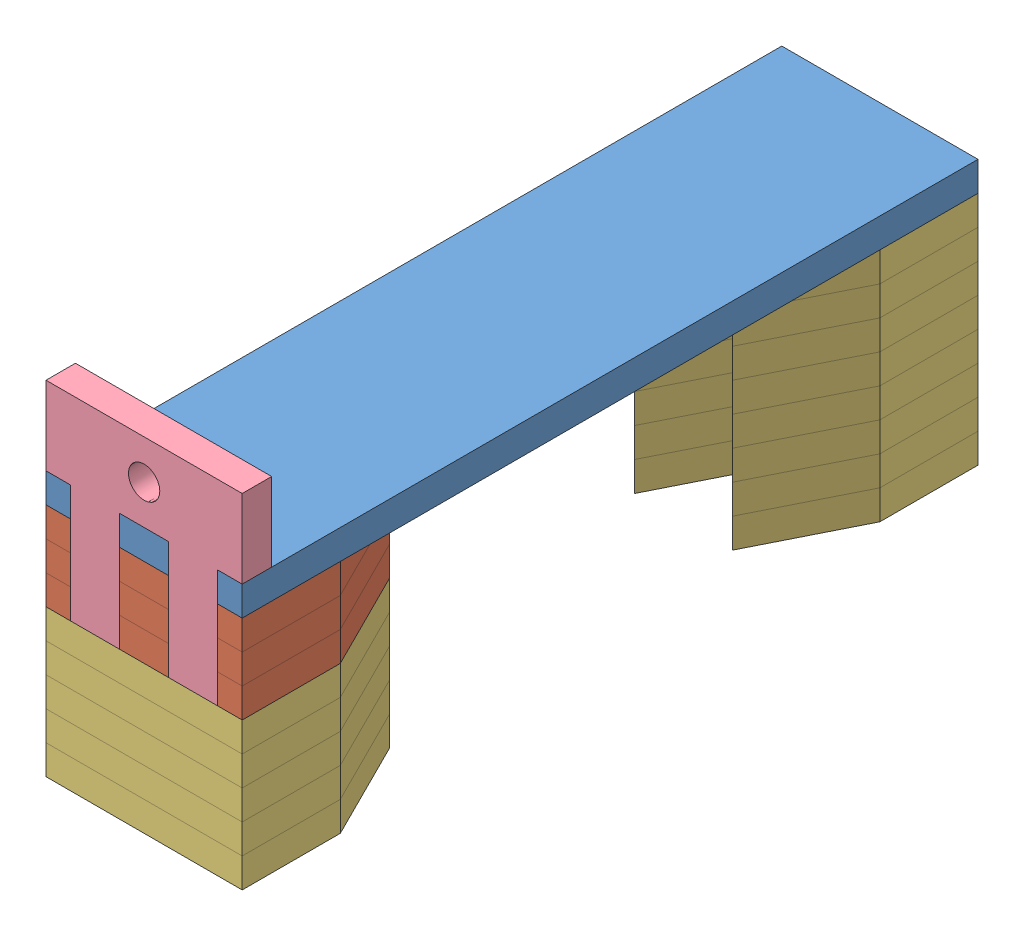
SolidWorks assembly piston, configuration Default. Lengths in mm.
Overall size (20 35 75).
18 component instances, 4 part files, 51 mates.
Components (placement in the parent):
- tooth-strip-1: tooth-strip [Default] at (26.7289 41.9083 55.3369) size (20 3 75)
- tooth-piston-1: tooth-piston [Default] at (26.7289 35.9083 82.8369) x (-1 0 0) z (0 0 -1) size (20 3 20)
- tooth-piston-2: tooth-piston [Default] at (26.7289 38.9083 82.8369) x (-1 0 0) z (0 0 -1) size (20 3 20)
- tooth-end-1: tooth-end [Default] at (26.7289 38.9083 27.8369) size (20 3 20)
- tooth-end-2: tooth-end [Default] at (26.7289 35.9083 27.8369) size (20 3 20)
- tooth-piston-3: tooth-piston [Default] at (26.7289 32.9083 82.8369) x (-1 0 0) z (0 0 -1) size (20 3 20)
- tooth-end-3: tooth-end [Default] at (26.7289 32.9083 27.8369) size (20 3 20)
- stopper-1: stopper [Default] at (16.7289 32.9083 89.8369) x (1 0 0) z (0 -1 0) size (20 3 20)
- tooth-end-4: tooth-end [Default] at (26.7289 29.9083 27.8369) size (20 3 20)
- tooth-end-5: tooth-end [Default] at (26.7289 29.9083 82.8369) x (-1 0 0) z (0 0 -1) size (20 3 20)
- tooth-end-6: tooth-end [Default] at (26.7289 26.9083 27.8369) size (20 3 20)
- tooth-end-7: tooth-end [Default] at (26.7289 23.9083 27.8369) size (20 3 20)
- tooth-end-8: tooth-end [Default] at (26.7289 26.9083 82.8369) x (-1 0 0) z (0 0 -1) size (20 3 20)
- tooth-end-9: tooth-end [Default] at (26.7289 23.9083 82.8369) x (-1 0 0) z (0 0 -1) size (20 3 20)
- tooth-end-10: tooth-end [Default] at (26.7289 20.9083 27.8369) size (20 3 20)
- tooth-end-11: tooth-end [Default] at (26.7289 17.9083 27.8369) size (20 3 20)
- tooth-end-12: tooth-end [Default] at (26.7289 20.9083 82.8369) x (-1 0 0) z (0 0 -1) size (20 3 20)
- tooth-end-13: tooth-end [Default] at (26.7289 17.9083 82.8369) x (-1 0 0) z (0 0 -1) size (20 3 20)
Mates (geometry in assembly coordinates):
- Coincident1: coincident anti-aligned: plane of tooth-strip-1 through (26.7289 41.9083 55.3369) normal (0 -1 0); plane of tooth-piston-2 through (26.7289 41.9083 82.8369) normal (0 1 0)
- Coincident2: coincident aligned: plane of tooth-strip-1 through (36.7289 44.9083 92.8369) normal (1 0 0); plane of tooth-piston-2 through (36.7289 41.9083 72.8369) normal (1 0 0)
- Coincident3: coincident aligned: plane of tooth-strip-1 through (16.7289 44.9083 92.8369) normal (0 0 1); plane of tooth-piston-2 through (36.7289 41.9083 92.8369) normal (0 0 1)
- Coincident4: coincident anti-aligned: plane of tooth-piston-1 through (26.7289 38.9083 82.8369) normal (0 1 0); plane of tooth-piston-2 through (26.7289 38.9083 82.8369) normal (0 -1 0)
- Coincident5: coincident aligned: plane of tooth-piston-1 through (36.7289 38.9083 72.8369) normal (1 0 0); plane of tooth-piston-2 through (36.7289 41.9083 72.8369) normal (1 0 0)
- Coincident6: coincident aligned: plane of tooth-piston-1 through (36.7289 38.9083 92.8369) normal (0 0 1); plane of tooth-piston-2 through (36.7289 41.9083 92.8369) normal (0 0 1)
- Coincident7: coincident anti-aligned: plane of tooth-strip-1 through (26.7289 41.9083 55.3369) normal (0 -1 0); plane of tooth-end-1 through (26.7289 41.9083 27.8369) normal (0 1 0)
- Coincident8: coincident aligned: plane of tooth-strip-1 through (16.7289 44.9083 17.8369) normal (0 0 -1); plane of tooth-end-1 through (16.7289 41.9083 17.8369) normal (0 0 -1)
- Coincident9: coincident aligned: plane of tooth-strip-1 through (36.7289 44.9083 92.8369) normal (1 0 0); plane of tooth-end-1 through (36.7289 41.9083 37.8369) normal (1 0 0)
- Coincident10: coincident anti-aligned: plane of tooth-end-1 through (26.7289 38.9083 27.8369) normal (0 -1 0); plane of tooth-end-2 through (26.7289 38.9083 27.8369) normal (0 1 0)
- Coincident11: coincident aligned: plane of tooth-end-1 through (36.7289 41.9083 37.8369) normal (1 0 0); plane of tooth-end-2 through (36.7289 38.9083 37.8369) normal (1 0 0)
- Coincident12: coincident aligned: plane of tooth-end-1 through (16.7289 41.9083 17.8369) normal (0 0 -1); plane of tooth-end-2 through (16.7289 38.9083 17.8369) normal (0 0 -1)
- Coincident17: coincident anti-aligned: plane of tooth-piston-1 through (26.7289 35.9083 82.8369) normal (0 -1 0); plane of tooth-piston-3 through (26.7289 35.9083 82.8369) normal (0 1 0)
- Coincident18: coincident aligned: plane of tooth-piston-1 through (36.7289 38.9083 72.8369) normal (1 0 0); plane of tooth-piston-3 through (36.7289 35.9083 72.8369) normal (1 0 0)
- Coincident19: coincident aligned: plane of tooth-piston-1 through (36.7289 38.9083 92.8369) normal (0 0 1); plane of tooth-piston-3 through (36.7289 35.9083 92.8369) normal (0 0 1)
- Coincident20: coincident anti-aligned: plane of tooth-end-2 through (26.7289 35.9083 27.8369) normal (0 -1 0); plane of tooth-end-3 through (26.7289 35.9083 27.8369) normal (0 1 0)
- Coincident21: coincident aligned: plane of tooth-end-2 through (36.7289 38.9083 37.8369) normal (1 0 0); plane of tooth-end-3 through (36.7289 35.9083 37.8369) normal (1 0 0)
- Coincident22: coincident aligned: plane of tooth-end-2 through (16.7289 38.9083 17.8369) normal (0 0 -1); plane of tooth-end-3 through (16.7289 35.9083 17.8369) normal (0 0 -1)
- Coincident23: coincident anti-aligned: plane of tooth-strip-1 through (29.2289 44.9083 89.8369) normal (0 0 1); plane of stopper-1 through (16.7289 32.9083 89.8369) normal (0 0 -1)
- Coincident25: coincident anti-aligned: plane of tooth-strip-1 through (26.7289 44.9083 55.3369) normal (0 1 0); plane of stopper-1 through (29.2289 44.9083 92.8369) normal (0 -1 0)
- Coincident26: coincident anti-aligned: plane of tooth-piston-1 through (34.2289 35.9083 92.8369) normal (-1 0 0); plane of stopper-1 through (34.2289 44.9083 92.8359) normal (1 0 0)
- Coincident27: coincident: plane of tooth-piston-3 through (26.7289 32.9083 82.8369) normal (0 -1 0); plane of tooth-end-5 through (26.7289 32.9083 82.8369) normal (0 1 0)
- Coincident28: coincident: plane of tooth-piston-3 through (36.7289 35.9083 72.8369) normal (1 0 0); plane of tooth-end-5 through (36.7289 32.9083 72.8369) normal (1 0 0)
- Coincident29: coincident aligned: plane of tooth-piston-3 through (36.7289 35.9083 92.8369) normal (0 0 1); plane of tooth-end-5 through (36.7289 32.9083 92.8369) normal (0 0 1)
- Coincident30: coincident: plane of tooth-end-3 through (26.7289 32.9083 27.8369) normal (0 -1 0); plane of tooth-end-4 through (26.7289 32.9083 27.8369) normal (0 1 0)
- Coincident31: coincident: plane of tooth-end-3 through (16.7289 35.9083 17.8369) normal (0 0 -1); plane of tooth-end-4 through (16.7289 32.9083 17.8369) normal (0 0 -1)
- Coincident32: coincident aligned: plane of tooth-end-3 through (34.7289 32.9083 31.8369) normal (0.894427 0 0.447214); plane of tooth-end-4 through (34.7289 29.9083 31.8369) normal (0.894427 0 0.447214)
- Coincident33: coincident: plane of tooth-end-5 through (26.7289 29.9083 82.8369) normal (0 -1 0); plane of tooth-end-8 through (26.7289 29.9083 82.8369) normal (0 1 0)
- Coincident34: coincident: plane of tooth-end-5 through (36.7289 32.9083 92.8369) normal (0 0 1); plane of tooth-end-8 through (36.7289 29.9083 92.8369) normal (0 0 1)
- Coincident35: coincident aligned: plane of tooth-end-5 through (36.7289 32.9083 72.8369) normal (1 0 0); plane of tooth-end-8 through (36.7289 29.9083 72.8369) normal (1 0 0)
- Coincident36: coincident: plane of tooth-end-8 through (26.7289 26.9083 82.8369) normal (0 -1 0); plane of tooth-end-9 through (26.7289 26.9083 82.8369) normal (0 1 0)
- Coincident37: coincident: plane of tooth-end-8 through (36.7289 29.9083 92.8369) normal (0 0 1); plane of tooth-end-9 through (36.7289 26.9083 92.8369) normal (0 0 1)
- Coincident38: coincident aligned: plane of tooth-end-8 through (36.7289 29.9083 72.8369) normal (1 0 0); plane of tooth-end-9 through (36.7289 26.9083 72.8369) normal (1 0 0)
- Coincident39: coincident: plane of tooth-end-4 through (26.7289 29.9083 27.8369) normal (0 -1 0); plane of tooth-end-6 through (26.7289 29.9083 27.8369) normal (0 1 0)
- Coincident40: coincident: plane of tooth-end-4 through (16.7289 32.9083 17.8369) normal (0 0 -1); plane of tooth-end-6 through (16.7289 29.9083 17.8369) normal (0 0 -1)
- Coincident41: coincident aligned: plane of tooth-end-4 through (36.7289 32.9083 37.8369) normal (1 0 0); plane of tooth-end-6 through (36.7289 29.9083 37.8369) normal (1 0 0)
- Coincident42: coincident: plane of tooth-end-6 through (26.7289 26.9083 27.8369) normal (0 -1 0); plane of tooth-end-7 through (26.7289 26.9083 27.8369) normal (0 1 0)
- Coincident43: coincident: plane of tooth-end-6 through (16.7289 29.9083 17.8369) normal (0 0 -1); plane of tooth-end-7 through (16.7289 26.9083 17.8369) normal (0 0 -1)
- Coincident44: coincident aligned: plane of tooth-end-6 through (36.7289 29.9083 37.8369) normal (1 0 0); plane of tooth-end-7 through (36.7289 26.9083 37.8369) normal (1 0 0)
- Coincident45: coincident: plane of tooth-end-9 through (26.7289 23.9083 82.8369) normal (0 -1 0); plane of tooth-end-12 through (26.7289 23.9083 82.8369) normal (0 1 0)
- Coincident46: coincident: plane of tooth-end-9 through (36.7289 26.9083 92.8369) normal (0 0 1); plane of tooth-end-12 through (36.7289 23.9083 92.8369) normal (0 0 1)
- Coincident47: coincident aligned: plane of tooth-end-9 through (36.7289 26.9083 72.8369) normal (1 0 0); plane of tooth-end-12 through (36.7289 23.9083 72.8369) normal (1 0 0)
- Coincident48: coincident: plane of tooth-end-12 through (26.7289 20.9083 82.8369) normal (0 -1 0); plane of tooth-end-13 through (26.7289 20.9083 82.8369) normal (0 1 0)
- Coincident49: coincident: plane of tooth-end-12 through (36.7289 23.9083 92.8369) normal (0 0 1); plane of tooth-end-13 through (36.7289 20.9083 92.8369) normal (0 0 1)
- Coincident50: coincident aligned: plane of tooth-end-12 through (36.7289 23.9083 72.8369) normal (1 0 0); plane of tooth-end-13 through (36.7289 20.9083 72.8369) normal (1 0 0)
- Coincident51: coincident: plane of tooth-end-7 through (26.7289 23.9083 27.8369) normal (0 -1 0); plane of tooth-end-10 through (26.7289 23.9083 27.8369) normal (0 1 0)
- Coincident52: coincident: plane of tooth-end-7 through (16.7289 26.9083 17.8369) normal (0 0 -1); plane of tooth-end-10 through (16.7289 23.9083 17.8369) normal (0 0 -1)
- Coincident53: coincident aligned: plane of tooth-end-7 through (36.7289 26.9083 37.8369) normal (1 0 0); plane of tooth-end-10 through (36.7289 23.9083 37.8369) normal (1 0 0)
- Coincident54: coincident: plane of tooth-end-10 through (26.7289 20.9083 27.8369) normal (0 -1 0); plane of tooth-end-11 through (26.7289 20.9083 27.8369) normal (0 1 0)
- Coincident55: coincident: plane of tooth-end-10 through (36.7289 23.9083 37.8369) normal (1 0 0); plane of tooth-end-11 through (36.7289 20.9083 37.8369) normal (1 0 0)
- Coincident56: coincident aligned: plane of tooth-end-10 through (16.7289 23.9083 17.8369) normal (0 0 -1); plane of tooth-end-11 through (16.7289 20.9083 17.8369) normal (0 0 -1)
